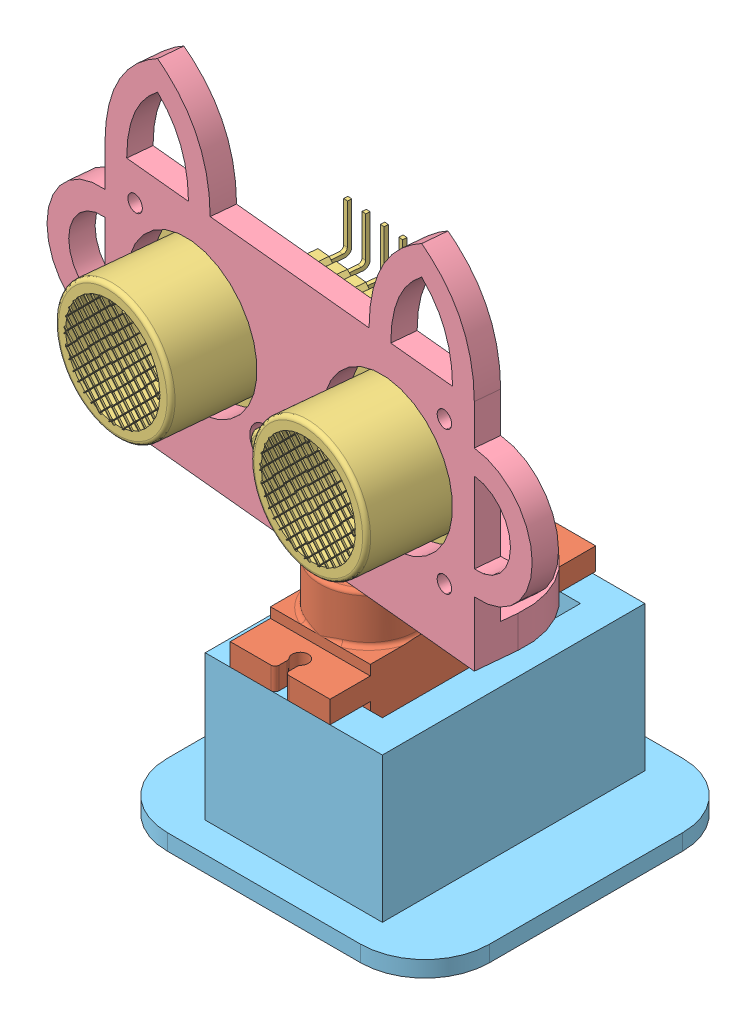
SolidWorks assembly radar, configuration Default. Lengths in mm.
Overall size (68.13 78.16 46.59).
5 component instances, 5 part files, 11 mates.
Components (placement in the parent):
- Micro Servo Horn Arm-1: Micro Servo Horn Arm [Default] at (33.7115 50.9816 21.4026) x (0.995396 0 0.095851) z (-0.095851 0 0.995396) size (36.39 4.27 7.53)
- Tower Pro MG90S Micro servo-1: Tower Pro MG90S Micro servo [Default] at (33.7115 26.6216 15.9026) size (13.01 32.65 33)
- Ultrasonic HCSR04-1: Ultrasonic HCSR04 [Default] at (-15.6429 -6.4139 21.1708) x (-0.995396 0 -0.095851) z (-0.095851 0 0.995396) size (45 24.45 19.22)
- ultrasonic holder-1: ultrasonic holder [Default] at (33.1364 71.2488 27.3749) x (0.995396 0 0.095851) z (0 -1 0) size (67 15 42.04)
- servo base-1: servo base [Default] at (34.4114 21.1216 15.1026) size (40 20 40)
Mates (geometry in assembly coordinates):
- Concentric1: concentric: circle of Micro Servo Horn Arm-1; circle of Tower Pro MG90S Micro servo-1
- Coincident1: coincident: plane of Micro Servo Horn Arm-1 through (4.7846 53.5216 18.6171) normal (0 -1 0); plane of Tower Pro MG90S Micro servo-1 through (35.946 53.5216 20.5266) normal (0 1 0)
- Concentric2: concentric: circle of Ultrasonic HCSR04-1; circle of ultrasonic holder-1
- Concentric3: concentric: circle of Ultrasonic HCSR04-1; circle of ultrasonic holder-1
- Concentric4: concentric: circle of Micro Servo Horn Arm-1; circle of ultrasonic holder-1
- Concentric5: concentric: circle of Micro Servo Horn Arm-1; circle of ultrasonic holder-1
- Coincident3: coincident: plane of Micro Servo Horn Arm-1 through (4.7846 55.2488 18.6171) normal (0 1 0); plane of ultrasonic holder-1 through (8.9041 55.2488 12.986) normal (0 -1 0)
- Coincident4: coincident: plane of Tower Pro MG90S Micro servo-1 through (27.5115 26.6216 27.4026) normal (0 0 1); plane of servo base-1 through (41.4114 39.1216 27.4026) normal (0 0 -1)
- Coincident5: coincident: plane of Tower Pro MG90S Micro servo-1 through (27.4114 31.8716 15.9026) normal (-1 0 0); plane of servo base-1 through (27.4114 39.1216 2.8026) normal (1 0 0)
- Coincident6: coincident: plane of Ultrasonic HCSR04-1 through (81.9349 -6.4139 33.38) normal (-0.095851 0 0.995396); plane of ultrasonic holder-1 through (33.0118 71.2488 28.669) normal (0.095851 0 -0.995396)
- Coincident7: coincident: plane of Tower Pro MG90S Micro servo-1 through (33.7115 21.1216 15.9026) normal (0 -1 0); plane of servo base-1 through (34.4114 21.1216 15.1026) normal (0 1 0)
